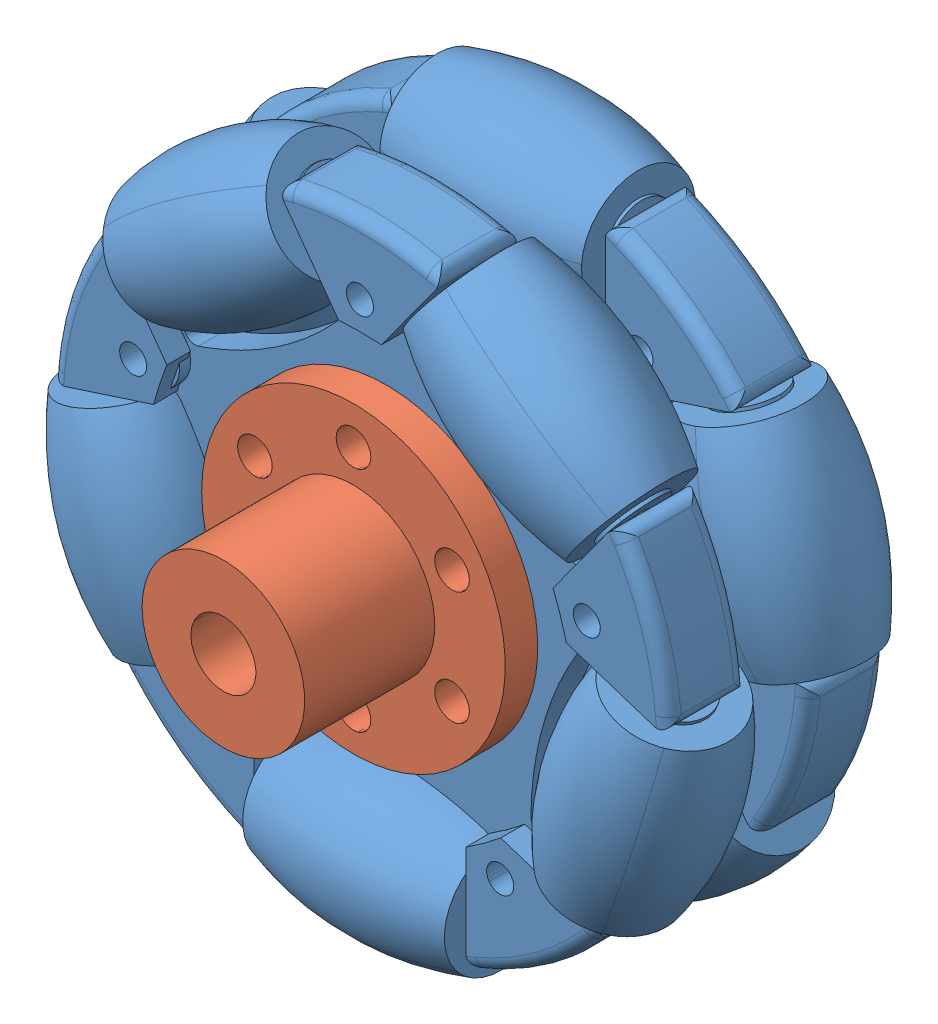
SolidWorks assembly 装配体2, configuration 默认. Lengths in mm.
Overall size (63.57 62.85 36.45).
2 component instances, 2 part files, 2 mates.
Components (placement in the parent):
- 60mm全向轮-1: 60mm全向轮 [默认] at (-33.7116 6.6664 -7.1915) size (63.57 62.85 28.43)
- 全向轮联轴器-1: 全向轮联轴器 [默认] at (-47.1495 14.6126 7.2348) size (28 28 15)
Mates (geometry in assembly coordinates):
- 同心1: concentric aligned: cylinder of 60mm全向轮-1 through (-47.1495 14.6126 7.2348) axis (0 0 -1) radius 6.25; cylinder of 全向轮联轴器-1 through (-47.1495 14.6126 22.2348) axis (0 0 -1) radius 3
- 重合1: coincident anti-aligned: plane of 60mm全向轮-1 through (-47.1495 14.6126 7.2348) normal (0 0 1); plane of 全向轮联轴器-1 through (-47.1495 14.6126 7.2348) normal (0 0 -1)
